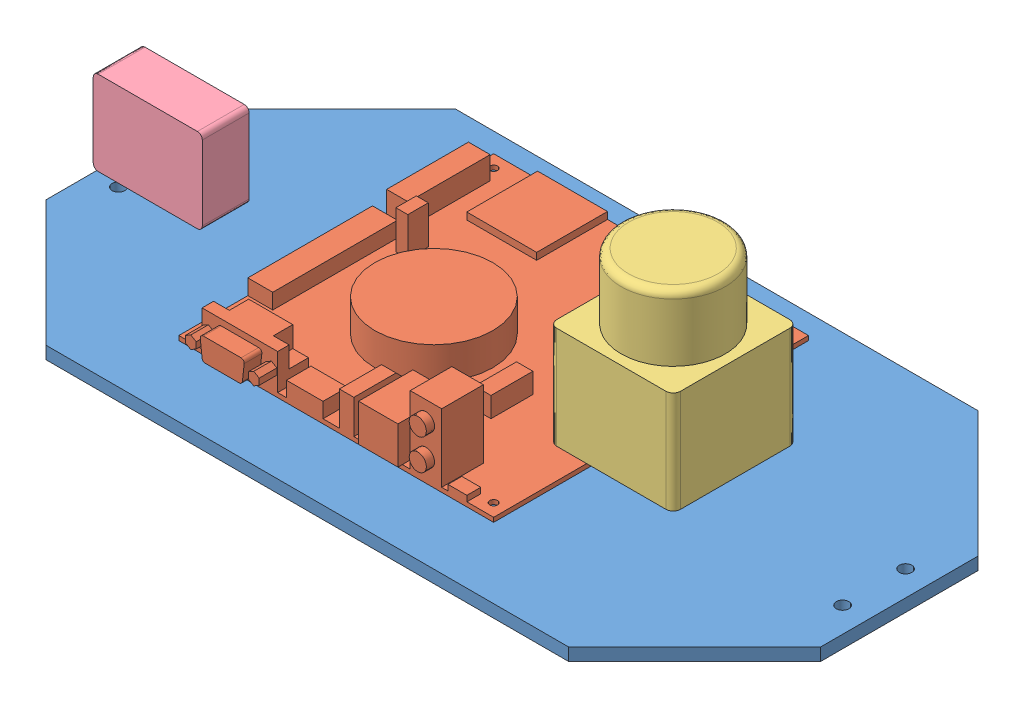
SolidWorks assembly Assem2, configuration Default. Lengths in mm.
Overall size (312.42 102.28 165.1).
4 component instances, 4 part files, 0 mates.
Components (placement in the parent):
- base_p-1: base_p [Default] at (11.8724 152.3989 223.5156) size (312.42 5.08 165.1)
- Jetson-1: Jetson [Default] at (84.5597 164.3627 284.5533) size (127 29.21 134.11)
- Lidar2-1: Lidar2 [Default] at (217.2589 186.93 267.8199) size (50 67.75 50)
- GreyCamera-1: GreyCamera [Default] at (15.6771 172.7933 250.1782) size (44 34 18.9)
